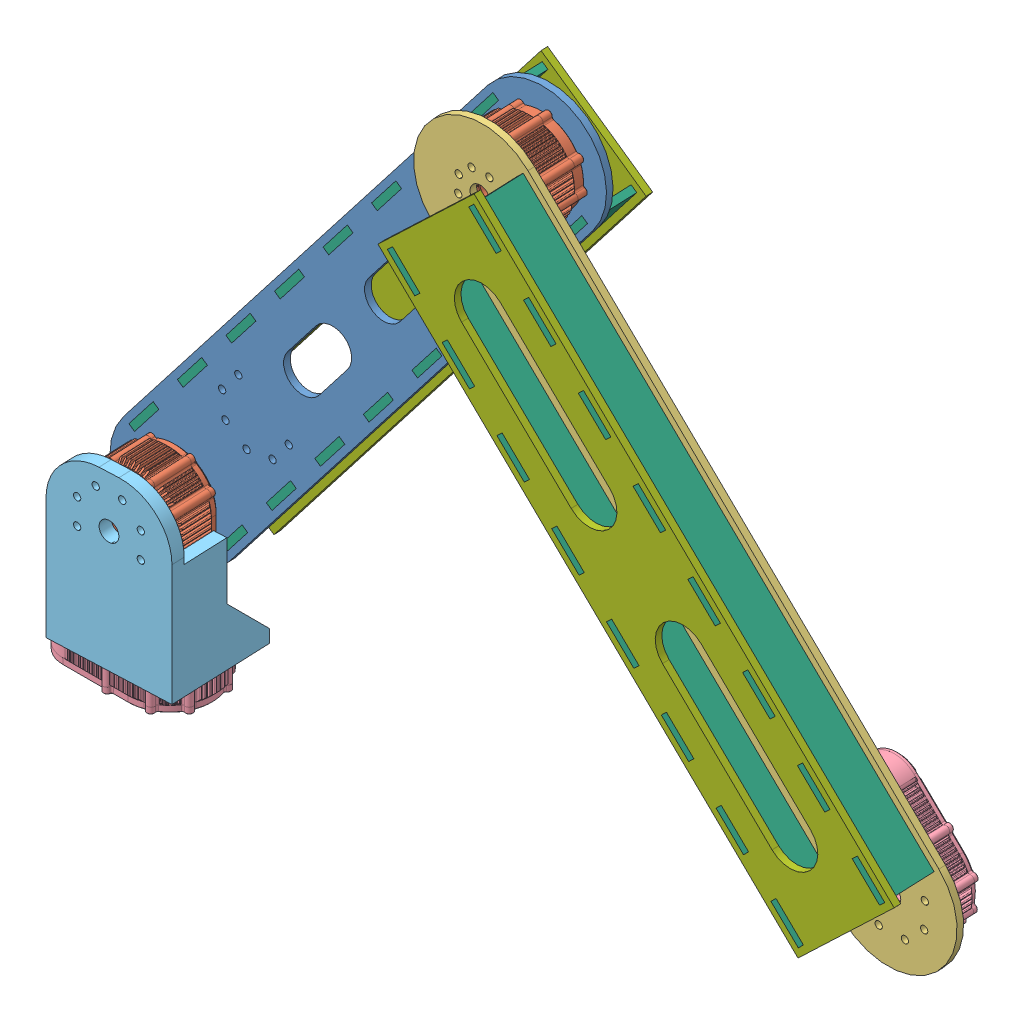
SolidWorks assembly Upper Arm Link Assembled, configuration Default. Lengths in mm.
Overall size (729.55 553.27 138.9).
13 component instances, 7 part files, 41 mates.
Components (placement in the parent):
- ME134 Robot Upper Arm-1: ME134 Robot Upper Arm [Default] at (147.3997 318.1807 -16.5707) x (0.609619 0.792292 -0.025277) z (0.041428 0 0.999141) size (550 100 5.4)
- HEBI Robotics-X8-Export-2021-1: HEBI Robotics-X8-Export-2021 [Default] at (0.7043 126.05 16.9854) x (0 -1 0) z (-0.041428 0 -0.999141) size (109.71 73.14 45.05)
- HEBI Robotics-X8-Export-2021-3: HEBI Robotics-X8-Export-2021 [Default] at (275.0721 482.5812 6.56) x (-0.609619 -0.792292 0.025277) z (0.041428 0 0.999141) size (109.71 73.14 45.05)
- ME134 Robot Lower Arm-2: ME134 Robot Lower Arm [Default] at (290.3655 467.3811 26.9439) x (0.68805 -0.725102 -0.028529) z (0.041428 0 0.999141) size (550 100 5.4)
- HEBI Robotics-X5-Export-1: HEBI Robotics-X5-Export [Default] at (584.9432 156.2851 -0.2832) x (-0.68805 0.725102 0.028529) z (-0.041428 0 -0.999141) size (109.71 73.14 31.05)
- ME134 Robot Base-1: ME134 Robot Base [Default] at (34.1891 -37.5671 38.6168) x (0 1 0) z (0.041428 0 0.999141) size (135 95 80)
- HEBI Robotics-X5-Export-2: HEBI Robotics-X5-Export [Default] at (0 15 0) x (-1 0 0) z (0 1 0) size (109.71 73.14 31.05)
- ME134 Arm Flange Short-1: ME134 Arm Flange Short [Default] at (-134.6929 26.2138 -21.6342) x (0.609619 0.792292 -0.025277) z (0.791611 -0.610143 -0.032823) size (450 45.8 5.4)
- ME134 Arm Flange Short-2: ME134 Arm Flange Short [Default] at (-67.7226 -25.4043 -24.411) x (0.609619 0.792292 -0.025277) z (0.791611 -0.610143 -0.032823) size (450 45.8 5.4)
- ME134 Arm Flange Short-3: ME134 Arm Flange Short [Default] at (137.6879 571.8088 56.9491) x (0.68805 -0.725102 -0.028529) z (-0.72448 -0.688641 0.030039) size (450 45.8 5.4)
- ME134 Arm Flange Short-4: ME134 Arm Flange Short [Default] at (725.7787 67.0576 32.5648) x (-0.68805 0.725102 0.028529) z (0.72448 0.688641 -0.030039) size (450 45.8 5.4)
- ME134 Outer Support Arm Flange-2: ME134 Outer Support Arm Flange [Default] at (137.5315 282.7778 -56.5962) x (0.609619 0.792292 -0.025277) z (0.041428 0 0.999141) size (460 100 5.4)
- ME134 Outer Support Arm Flange-3: ME134 Outer Support Arm Flange [Default] at (410.7838 320.3106 62.3856) x (0.68805 -0.725102 -0.028529) z (0.041428 0 0.999141) size (460 100 5.4)
Mates (geometry in assembly coordinates):
- Coincident16: coincident anti-aligned: plane of HEBI Robotics-X8-Export-2021-3 through (275.9421 482.5812 27.5419) normal (0.041428 0 0.999141); plane of ME134 Robot Lower Arm-2 through (290.3655 467.3811 26.9439) normal (-0.041428 0 -0.999141)
- Concentric7: concentric anti-aligned: cylinder of HEBI Robotics-X8-Export-2021-3 through (274.4498 482.5812 -8.4484) axis (0.041428 0 0.999141) radius 7.5; cylinder of ME134 Robot Lower Arm-2 through (276.1658 482.5812 32.9373) axis (-0.041428 0 -0.999141) radius 7.5
- Coincident24: coincident anti-aligned: plane of ME134 Robot Lower Arm-2 through (290.3655 467.3811 26.9439) normal (-0.041428 0 -0.999141); plane of HEBI Robotics-X5-Export-1 through (585.5646 156.2851 14.7039) normal (0.041428 0 0.999141)
- Concentric8: concentric aligned: cylinder of ME134 Robot Lower Arm-2 through (585.7883 156.2851 20.0993) axis (-0.041428 0 -0.999141) radius 7.5; cylinder of HEBI Robotics-X5-Export-1 through (585.3583 156.2851 9.7294) axis (-0.041428 0 -0.999141) radius 7.5
- Coincident25: coincident anti-aligned: plane of HEBI Robotics-X8-Export-2021-1 through (1.6571 126.05 39.9657) normal (0.041428 0 0.999141); plane of ME134 Robot Base-1 through (9.1507 126.05 39.655) normal (-0.041428 0 -0.999141)
- Concentric10: concentric aligned: cylinder of HEBI Robotics-X8-Export-2021-1 through (1.3266 126.05 31.9938) axis (-0.041428 0 -0.999141) radius 7.5; cylinder of ME134 Robot Base-1 through (2.0714 126.05 49.9571) axis (-0.041428 0 -0.999141) radius 7.5
- Concentric11: concentric anti-aligned: cylinder of HEBI Robotics-X8-Export-2021-1 through (-8.3343 152.05 40.3799) axis (0.041428 0 0.999141) radius 2.1; cylinder of ME134 Robot Base-1 through (-7.92 152.05 50.3714) axis (-0.041428 0 -0.999141) radius 2.75
- Coincident26: coincident anti-aligned: plane of ME134 Robot Base-1 through (-45.3878 31.05 51.9249) normal (0 -1 0); plane of HEBI Robotics-X5-Export-2 through (0 31.05 0) normal (0 1 0)
- Concentric12: concentric anti-aligned: cylinder of ME134 Robot Base-1 through (0 74.85 0) axis (0 -1 0) radius 7.5; cylinder of HEBI Robotics-X5-Export-2 through (0 4.9787 0) axis (0 1 0) radius 7.5
- Coincident29: coincident anti-aligned: plane of ME134 Robot Lower Arm-2 through (261.0239 355.3433 54) normal (0.863749 0.503923 0); plane of ME134 Arm Flange-3 through (486.126 -29.0104 59.146) normal (-0.863749 -0.503923 0)
- Width5: width aligned: plane of ME134 Arm Flange-3 through (486.126 -29.0104 54.27) normal (0 0 -1); plane of ME134 Robot Lower Arm-2 through (486.126 -29.0104 48.73) normal (0 0 1); plane of ME134 Arm Flange-3 through (290.3655 467.3811 26.9439) normal (-0.041428 0 -0.999141); plane of ME134 Robot Lower Arm-2 through (290.5892 467.3811 32.3393) normal (0.041428 0 0.999141)
- Width8: width aligned: plane of ME134 Robot Lower Arm-2 through (322.2005 172.1778 54) normal (0.503923 -0.863749 0); plane of ME134 Arm Flange-3 through (337.3181 146.2653 54) normal (-0.503923 0.863749 0); plane of ME134 Robot Lower Arm-2 through (373.0082 164.8793 59.146) normal (0.503923 -0.863749 0); plane of ME134 Arm Flange-3 through (357.8905 190.7918 59.146) normal (-0.503923 0.863749 0)
- Coincident30: coincident anti-aligned: plane of ME134 Robot Lower Arm-2 through (192.8568 315.5737 54) normal (-0.863749 -0.503923 0); plane of ME134 Arm Flange-4 through (176.6056 344.9119 59.146) normal (0.863749 0.503923 0)
- Width10: width aligned: plane of ME134 Robot Lower Arm-2 through (322.2005 172.1778 54) normal (0.503923 -0.863749 0); plane of ME134 Arm Flange-4 through (337.3181 146.2653 54) normal (-0.503923 0.863749 0); plane of ME134 Robot Lower Arm-2 through (289.7234 151.0222 59.146) normal (-0.503923 0.863749 0); plane of ME134 Arm Flange-4 through (304.8411 125.1098 59.146) normal (0.503923 -0.863749 0)
- Width11: width aligned: plane of ME134 Arm Flange-4 through (176.6056 344.9119 54.27) normal (0 0 -1); plane of ME134 Robot Lower Arm-2 through (176.6056 344.9119 48.73) normal (0 0 1); plane of ME134 Arm Flange-4 through (290.3655 467.3811 26.9439) normal (-0.041428 0 -0.999141); plane of ME134 Robot Lower Arm-2 through (290.5892 467.3811 32.3393) normal (0.041428 0 0.999141)
- Concentric13: concentric aligned: cylinder of ME134 Robot Upper Arm-1 through (-0.2092 126.05 -5.0457) axis (-0.041428 0 -0.999141) radius 7.5; cylinder of HEBI Robotics-X8-Export-2021-1 through (1.3266 126.05 31.9938) axis (-0.041428 0 -0.999141) radius 7.5
- Coincident31: coincident anti-aligned: plane of ME134 Robot Upper Arm-1 through (147.6234 318.1807 -11.1753) normal (0.041428 0 0.999141); plane of HEBI Robotics-X8-Export-2021-1 through (-0.2092 126.05 -5.0457) normal (-0.041428 0 -0.999141)
- Coincident32: coincident anti-aligned: plane of ME134 Robot Upper Arm-1 through (147.6234 318.1807 -11.1753) normal (0.041428 0 0.999141); plane of HEBI Robotics-X8-Export-2021-3 through (274.1193 482.5812 -16.4203) normal (-0.041428 0 -0.999141)
- Concentric14: concentric anti-aligned: cylinder of ME134 Robot Upper Arm-1 through (274.1193 482.5812 -16.4203) axis (-0.041428 0 -0.999141) radius 7.5; cylinder of HEBI Robotics-X8-Export-2021-3 through (274.4498 482.5812 -8.4484) axis (0.041428 0 0.999141) radius 7.5
- Concentric15: concentric aligned: cylinder of ME134 Robot Upper Arm-1 through (288.241 461.5994 -17.0058) axis (-0.041428 0 -0.999141) radius 2.75; cylinder of HEBI Robotics-X8-Export-2021-3 through (288.241 461.5994 -17.0058) axis (-0.041428 0 -0.999141) radius 2.1
- Coincident33: coincident anti-aligned: plane of ME134 Robot Upper Arm-1 through (147.3997 318.1807 -16.5707) normal (-0.041428 0 -0.999141); plane of ME134 Arm Flange Short-1 through (205.9706 459.2054 -18.9992) normal (0.041428 0 0.999141)
- Coincident34: coincident anti-aligned: plane of ME134 Robot Upper Arm-1 through (274.1193 482.5812 -16.4203) normal (-0.609619 -0.792292 0.025277); plane of ME134 Arm Flange Short-1 through (242.5478 506.7428 -20.5159) normal (0.609619 0.792292 -0.025277)
- Coincident36: coincident anti-aligned: line of ME134 Robot Upper Arm-1 through (220.2082 486.2689 -14.1849) axis (0.609619 0.792292 -0.025277); line of ME134 Arm Flange Short-1 through (238.4968 510.0376 -14.9433) axis (-0.609619 -0.792292 0.025277)
- Coincident37: coincident anti-aligned: plane of ME134 Robot Upper Arm-1 through (147.3997 318.1807 -16.5707) normal (-0.041428 0 -0.999141); plane of ME134 Arm Flange Short-2 through (272.941 407.5873 -21.7761) normal (0.041428 0 0.999141)
- Coincident38: coincident anti-aligned: plane of ME134 Robot Upper Arm-1 through (274.1193 482.5812 -16.4203) normal (-0.609619 -0.792292 0.025277); plane of ME134 Arm Flange Short-2 through (309.5181 455.1248 -23.2927) normal (0.609619 0.792292 -0.025277)
- Coincident39: coincident anti-aligned: line of ME134 Robot Upper Arm-1 through (287.1785 434.6508 -16.9618) axis (0.609619 0.792292 -0.025277); line of ME134 Arm Flange Short-2 through (305.4671 458.4195 -17.7201) axis (-0.609619 -0.792292 0.025277)
- Coincident40: coincident anti-aligned: plane of ME134 Robot Lower Arm-2 through (290.5892 467.3811 32.3393) normal (0.041428 0 0.999141); plane of ME134 Arm Flange Short-3 through (264.2057 429.8393 33.4332) normal (-0.041428 0 -0.999141)
- Coincident41: coincident anti-aligned: plane of ME134 Robot Lower Arm-2 through (243.3405 451.5923 28.8937) normal (0.68805 -0.725102 -0.028529); plane of ME134 Arm Flange Short-3 through (243.5642 451.5923 34.2891) normal (-0.68805 0.725102 0.028529)
- Coincident42: coincident aligned: line of ME134 Robot Lower Arm-2 through (243.3405 451.5923 28.8937) axis (0.68805 -0.725102 -0.028529); line of ME134 Arm Flange Short-3 through (243.3405 451.5923 28.8937) axis (0.68805 -0.725102 -0.028529)
- Coincident43: coincident anti-aligned: plane of ME134 Robot Lower Arm-2 through (290.5892 467.3811 32.3393) normal (0.041428 0 0.999141); plane of ME134 Arm Flange Short-4 through (350.0504 470.0639 29.8738) normal (-0.041428 0 -0.999141)
- Coincident44: coincident anti-aligned: plane of ME134 Robot Lower Arm-2 through (308.5437 513.57 26.1902) normal (0.68805 -0.725102 -0.028529); plane of ME134 Arm Flange Short-4 through (310.2174 513.57 66.5555) normal (-0.68805 0.725102 0.028529)
- Coincident45: coincident aligned: line of ME134 Robot Lower Arm-2 through (329.1852 491.817 25.3343) axis (-0.68805 0.725102 0.028529); line of ME134 Arm Flange Short-4 through (329.1852 491.817 25.3343) axis (-0.68805 0.725102 0.028529)
- Coincident49: coincident anti-aligned: plane of HEBI Robotics-X5-Export-2 through (0 0 0) normal (0 -1 0)
- Coincident51: coincident aligned: plane of HEBI Robotics-X5-Export-2 through (0 15 0) normal (0 0 1)
- Coincident52: coincident anti-aligned: plane of HEBI Robotics-X5-Export-2 through (0 15 0) normal (-1 0 0)
- Coincident55: coincident anti-aligned: plane of ME134 Arm Flange Short-1 through (204.5207 459.2054 -53.9692) normal (-0.041428 0 -0.999141); plane of ME134 Outer Support Arm Flange-2 through (137.7552 282.7778 -51.2009) normal (0.041428 0 0.999141)
- Coincident56: coincident anti-aligned: plane of ME134 Arm Flange Short-1 through (222.8092 482.9741 -54.7275) normal (-0.609619 -0.792292 0.025277); plane of ME134 Outer Support Arm Flange-2 through (218.5345 486.2689 -54.5503) normal (0.609619 0.792292 -0.025277)
- Coincident57: coincident anti-aligned: line of ME134 Arm Flange Short-1 through (218.3108 486.2689 -59.9456) axis (0.609619 0.792292 -0.025277); line of ME134 Outer Support Arm Flange-2 through (236.5994 510.0376 -60.7039) axis (-0.609619 -0.792292 0.025277)
- Coincident58: coincident anti-aligned: plane of ME134 Arm Flange Short-4 through (392.7834 426.5578 63.132) normal (0.041428 0 0.999141); plane of ME134 Outer Support Arm Flange-3 through (410.7838 320.3106 62.3856) normal (-0.041428 0 -0.999141)
- Coincident59: coincident anti-aligned: line of ME134 Arm Flange Short-4 through (310.4411 513.57 71.9508) axis (0.68805 -0.725102 -0.028529); line of ME134 Outer Support Arm Flange-3 through (331.0826 491.817 71.095) axis (-0.68805 0.725102 0.028529)
- Coincident60: coincident anti-aligned: plane of ME134 Arm Flange Short-4 through (330.8589 491.817 65.6996) normal (0.68805 -0.725102 -0.028529); plane of ME134 Outer Support Arm Flange-3 through (331.0826 491.817 71.095) normal (-0.68805 0.725102 0.028529)
